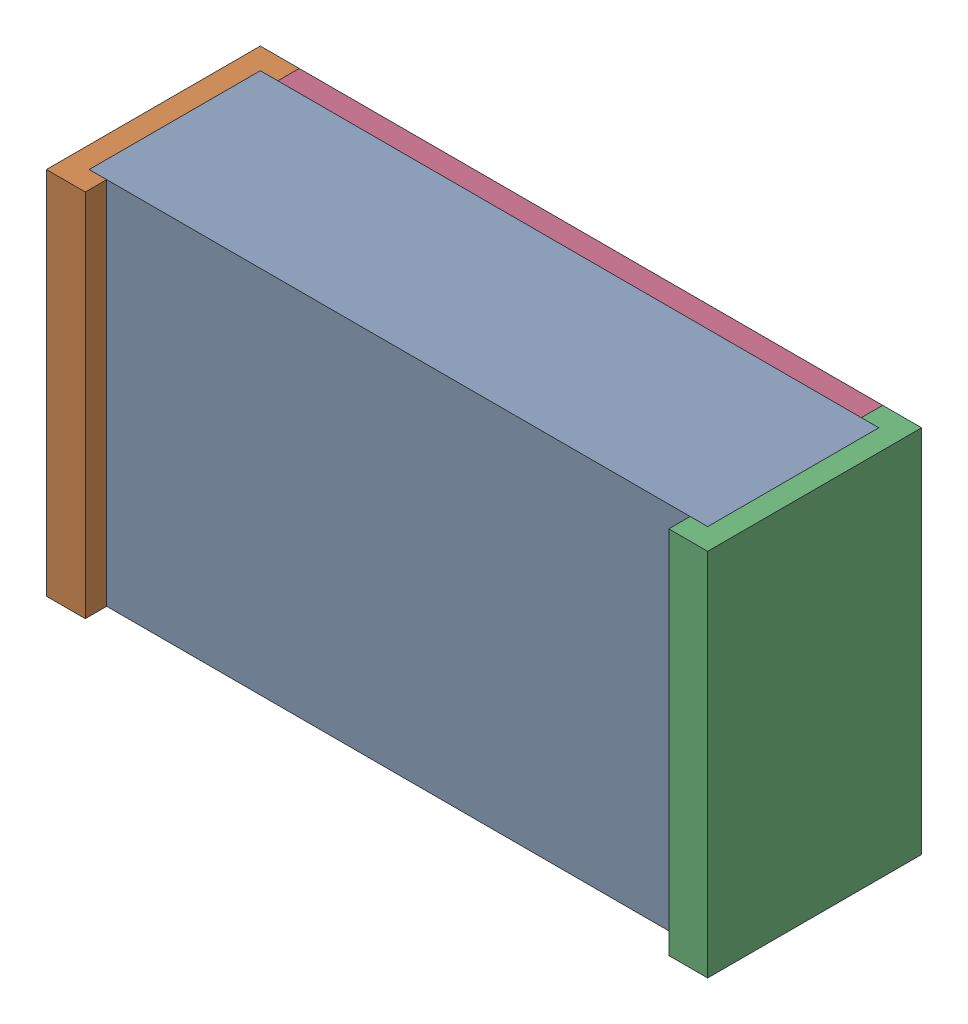
SolidWorks assembly R6, configuration Default. Lengths in mm.
Overall size (1.7 0.95 0.55).
7 component instances, 3 part files, 0 mates.
Components (placement in the parent):
- 7434017360-1: 7434017360 [Default] at (141 90 -1.6914) x (1 0 0) z (0 0 -1) size (1.7 0.95 0.55)
  - Mid_Body-1: Mid_Body [Default] at (-0.85 -0.475 0) size (1.59 0.95 0.44)
  - Terminal-1: Terminal [Default] at (-0.85 -0.475 0) size (0.1 0.95 0.55)
    - Open_CASCADE_STEP_translator_6.8_1.2.1-1: Open_CASCADE_STEP_translator_6.8_1.2.1 [Default] at origin size (0.1 0.95 0.55)
  - Terminal-2: Terminal [Default] at (0.85 0.475 0) x (-1 0 0) z (0 0 1) size (0.1 0.95 0.55)
    - Open_CASCADE_STEP_translator_6.8_1.2.1-1: Open_CASCADE_STEP_translator_6.8_1.2.1 [Default] at origin size (0.1 0.95 0.55)
  - Mark-1: Mark [Default] at (-0.75 -0.475 0.495) size (1.5 0.95 0.06)
